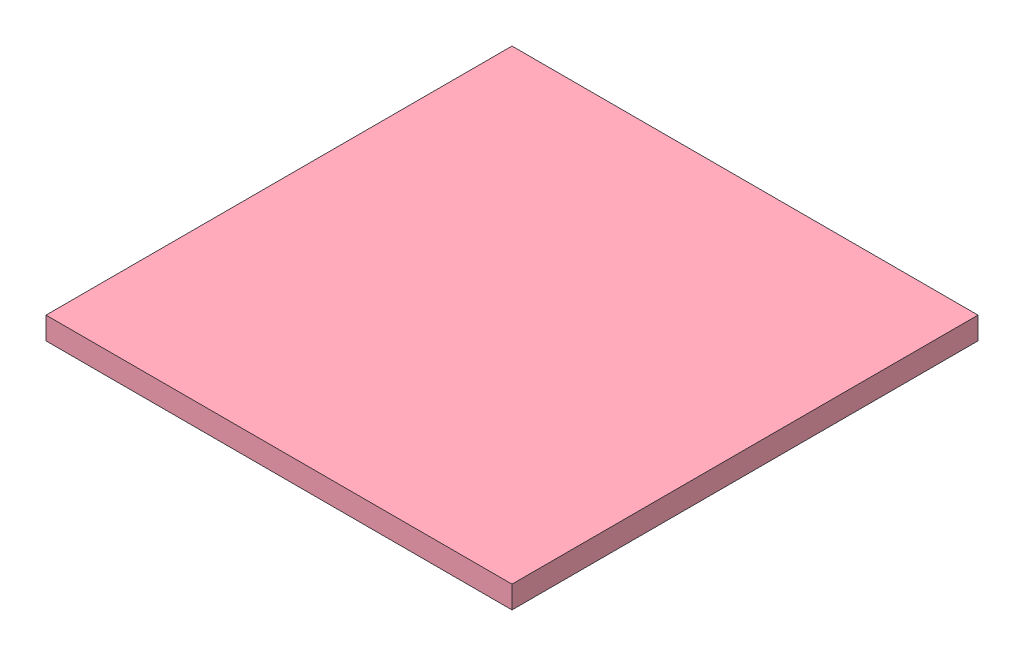
SolidWorks assembly Buildplate, configuration Default. Lengths in mm.
Overall size (250 48 250).
29 component instances, 7 part files, 0 mates.
Components (placement in the parent):
- Buildplate_frame-2: Buildplate_frame [Default] at (0 11 0) x (1 0 0) z (0 0 -1) size (220 6 220)
- SCS8UU-1: SCS8UU [Default] at (-85.5 0 36.5) size (34 22 30)
- SCS8UU-2: SCS8UU [Default] at (85.5 0 36.5) size (34 22 30)
- SCS8UU-3: SCS8UU [Default] at (-85.5 0 -36.5) size (34 22 30)
- SCS8UU-4: SCS8UU [Default] at (85.5 0 -36.5) size (34 22 30)
- M4x7_PH-1: M4x7_PH [Default] at (-97.5 14 45.5) size (6 9.66 6)
- M4x7_PH-2: M4x7_PH [Default] at (-73.5 14 45.5) size (6 9.66 6)
- M4x7_PH-3: M4x7_PH [Default] at (-97.5 14 27.5) size (6 9.66 6)
- M4x7_PH-4: M4x7_PH [Default] at (73.5 14 45.5) size (6 9.66 6)
- M4x7_PH-5: M4x7_PH [Default] at (73.5 14 27.5) size (6 9.66 6)
- M4x7_PH-6: M4x7_PH [Default] at (-73.5 14 27.5) size (6 9.66 6)
- M4x7_PH-7: M4x7_PH [Default] at (97.5 14 45.5) size (6 9.66 6)
- M4x7_PH-8: M4x7_PH [Default] at (97.5 14 27.5) size (6 9.66 6)
- M4x7_PH-9: M4x7_PH [Default] at (-97.5 14 -27.5) size (6 9.66 6)
- M4x7_PH-10: M4x7_PH [Default] at (-73.5 14 -27.5) size (6 9.66 6)
- M4x7_PH-11: M4x7_PH [Default] at (-97.5 14 -45.5) size (6 9.66 6)
- M4x7_PH-12: M4x7_PH [Default] at (73.5 14 -27.5) size (6 9.66 6)
- M4x7_PH-13: M4x7_PH [Default] at (73.5 14 -45.5) size (6 9.66 6)
- M4x7_PH-14: M4x7_PH [Default] at (-73.5 14 -45.5) size (6 9.66 6)
- M4x7_PH-15: M4x7_PH [Default] at (97.5 14 -27.5) size (6 9.66 6)
- M4x7_PH-16: M4x7_PH [Default] at (97.5 14 -45.5) size (6 9.66 6)
- MDF_plate-1: MDF_plate [Default] at (0 14 0) size (250 12 250)
- TR8_nut_assembly-1: TR8_nut_assembly [Default] at (0 -22 0) size (30 33.25 30)
  - TR8_holder-1: TR8_holder [Default] at origin size (30 30 30)
  - TR8_lead_screw-1: TR8_lead_screw [Default] at (0 12 1.75) size (22 22 16.4)
  - M4x14_PH-1: M4x14_PH [Default] at (6 19.25 -10) x (1 0 0) z (0 0 -1) size (6 16.66 6)
  - M4x14_PH-2: M4x14_PH [Default] at (-6 19.25 -10) x (1 0 0) z (0 0 -1) size (6 16.66 6)
  - M4x14_PH-3: M4x14_PH [Default] at (6 19.25 10) x (1 0 0) z (0 0 -1) size (6 16.66 6)
  - M4x14_PH-4: M4x14_PH [Default] at (-6 19.25 10) x (1 0 0) z (0 0 -1) size (6 16.66 6)
